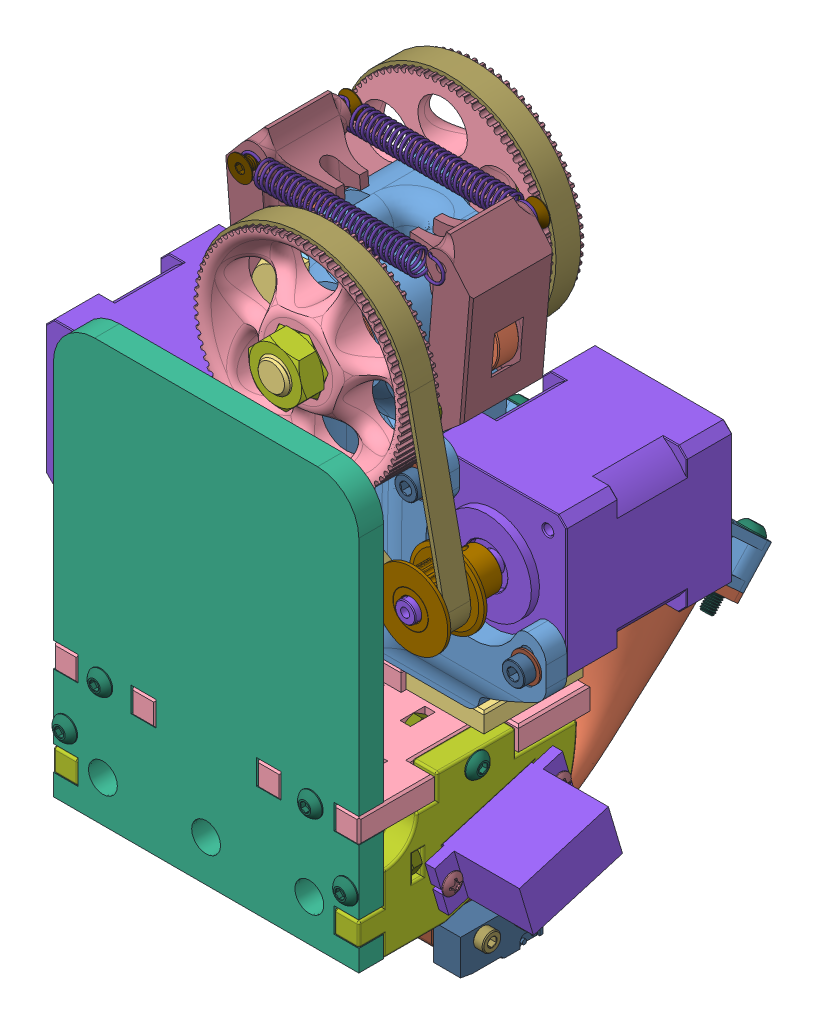
SolidWorks assembly Assembly Instructions, configuration Assemble Idler block. Lengths in mm.
Overall size (108.39 160.35 121.94).
110 component instances, 40 part files, 35 mates.
Components (placement in the parent):
- IttyBittyDoubleExtruderAssembly-1: IttyBittyDoubleExtruderAssembly [Default] at origin size (106.39 98.03 74.25)
  - IttyBittyDoubleExtruderBlock-1: IttyBittyDoubleExtruderBlock [Default] at origin size (106.2 79.3 54.92)
  - Bearing-688-1: Bearing-688 [7804K117] at (-8 64.4888 10.5) size (16 16 5)
  - Bearing-688-2: Bearing-688 [7804K117] at (8 64.4888 16.5) size (16 16 5)
  - Bearing-688-3: Bearing-688 [7804K117] at (8 64.4888 -10.5) size (16 16 5)
  - Bearing-688-4: Bearing-688 [7804K117] at (-8 64.4888 -16.5) size (16 16 5)
  - HobbedBolt-1: HobbedBolt [Default] at (8 64.4888 -14) x (0.945139 -0.326669 0) z (0 0 1) size (14.66 12.7 56.13)
  - Parametric-Pulley-80-8-hex-1: Parametric-Pulley-80-8-hex [Default] at (8 64.4888 32) x (0.986927 0.161169 0) z (0 0 -1) size (50.4 50.4 9.47)
  - Spacer 1mm-1: Spacer 1mm [Default] at (8 64.4888 -14) size (13 13 1)
  - Spacer 2mm-1: Spacer 2mm [Default] at (8 64.4888 19) size (13 13 2)
  - HobbedBolt-2: HobbedBolt [Default] at (-8 64.4888 14) x (-0.397408 -0.917642 0) z (0 0 -1) size (14.66 12.7 56.13)
  - Parametric-Pulley-80-8-hex-2: Parametric-Pulley-80-8-hex [Default] at (-8 64.4888 -32) x (1 0 0) z (0 0 1) size (50.4 50.4 9.47)
  - Spacer 1mm-2: Spacer 1mm [Default] at (-8 64.4888 14) x (-0.923728 -0.383049 0) z (0 0 -1) size (13 13 1)
  - Spacer 2mm-2: Spacer 2mm [Default] at (-8 64.4888 -21) size (13 13 2)
  - 5-16-Nut-1: 5-16-Nut [Default] at (-8 64.4888 -30.3) size (14.66 12.7 5.2)
  - 5-16-Nut-2: 5-16-Nut [Default] at (8 64.4888 25.1) x (0.353886 0.935288 0) z (0 0 1) size (14.66 12.7 5.2)
  - 5-16-Nut-3: 5-16-Nut [Default] at (8 64.4888 30.3) x (0.969294 -0.245906 0) z (0 0 1) size (14.66 12.7 5.2)
  - 5-16-Nut-4: 5-16-Nut [Default] at (-8 64.4888 -35.5) x (0.948708 -0.316153 0) z (0 0 1) size (14.66 12.7 5.2)
  - NEMA14 Stepper Motor-1: NEMA14 Stepper Motor [Default] at (17.9692 8.8788 -30.1574) x (-1 0 0) z (0 1 0) size (36.32 61.75 35.05)
  - GT2_20tooth-1: GT2_20tooth [Default] at (35.4952 26.4048 12.75) x (0 0 1) z (-0.834274 -0.551351 0) size (17.5 18 18)
  - GT2_20tooth-2: GT2_20tooth [Default] at (-35.4952 26.4048 -12.75) x (0 0 -1) z (0.834274 -0.551351 0) size (17.5 18 18)
  - NEMA14 Stepper Motor-2: NEMA14 Stepper Motor [Default] at (-17.9692 8.8788 30.1574) x (1 0 0) z (0 1 0) size (36.32 61.75 35.05)
  - M3x10HexCapScrew-1: M3x10HexCapScrew [91290A115] at (22.5 13.4 5.45) x (-0.709862 0.70434 0) z (0 0 -1) size (5.5 5.5 13.21)
  - M3Washer-1: M3Washer [91166A210] at (22.5 13.4 15) x (0.895294 -0.445476 0) z (0 0 -1) size (7 7 0.45)
  - M3Washer-12: M3Washer [91166A210] at (-22.5 13.4 -15) x (-0.895294 -0.445476 0) z (0 0 1) size (7 7 0.45)
  - M3x10HexCapScrew-5: M3x10HexCapScrew [91290A115] at (-22.5 13.4 -5.45) x (0.709862 0.70434 0) z (0 0 1) size (5.5 5.5 13.21)
  - M3Washer-13: M3Washer [91166A210] at (22.5 39.4 15) x (0.895294 -0.445476 0) z (0 0 -1) size (7 7 0.45)
  - M3Washer-14: M3Washer [91166A210] at (48.5 13.4 15) x (0.895294 -0.445476 0) z (0 0 -1) size (7 7 0.45)
  - M3x10HexCapScrew-6: M3x10HexCapScrew [91290A115] at (22.5 39.4 5.45) x (-0.709862 0.70434 0) z (0 0 -1) size (5.5 5.5 13.21)
  - M3x10HexCapScrew-7: M3x10HexCapScrew [91290A115] at (48.5 13.4 5.45) x (-0.709862 0.70434 0) z (0 0 -1) size (5.5 5.5 13.21)
  - M3Washer-16: M3Washer [91166A210] at (-22.5 39.4 -15) x (-0.895294 -0.445476 0) z (0 0 1) size (7 7 0.45)
  - M3Washer-17: M3Washer [91166A210] at (-48.5 13.4 -15) x (-0.895294 -0.445476 0) z (0 0 1) size (7 7 0.45)
  - M3x10HexCapScrew-9: M3x10HexCapScrew [91290A115] at (-22.5 39.4 -5.45) x (0.709862 0.70434 0) z (0 0 1) size (5.5 5.5 13.21)
  - M3x10HexCapScrew-10: M3x10HexCapScrew [91290A115] at (-48.5 13.4 -5.45) x (0.709862 0.70434 0) z (0 0 1) size (5.5 5.5 13.21)
  - DriveBelt-1: DriveBelt [Default] at (0 0 25.5) x (-1 0 0) z (0 0 -1) size (60.34 70.93 6)
  - DriveBelt-2: DriveBelt [Default] at (0 0 -25.5) size (60.34 70.93 6)
  - IdlerBlock-1: IdlerBlock [Default] at (21.104 63.5553 0) x (-0.996453 0.084148 0) z (0 0 -1) size (20.98 41.13 20.11)
  - Bearing-688-5: Bearing-688 [7804K117] at (21.104 63.5553 0) x (0.754304 -0.656525 0) z (0 0 1) size (16 16 5)
  - IdlerPin-15mm-1: IdlerPin-15mm [Default] at (21.104 63.5553 0) x (-0.996453 0.084148 0) z (0 0 1) size (7.5 8 15.6)
  - M3x25-1: M3x25 [91290A125] at (20.0438 51 15) x (0.098651 -0.995122 0) z (0 0 1) size (5.5 5.5 28.26)
  - M3HexNut-1: M3HexNut [90591A121] at (20.0438 51 11.2) x (0.996239 -0.086644 0) z (-0.086644 -0.996239 0) size (5.5 2.58 6.35)
  - M3HexNut-2: M3HexNut [90591A121] at (-20.0438 51 -11.2) x (-0.996239 -0.086644 0) z (0.086644 -0.996239 0) size (5.5 2.58 6.35)
  - M3x25-2: M3x25 [91290A125] at (-20.0438 51 -15) x (-0.098651 -0.995122 0) z (0 0 -1) size (5.5 5.5 28.26)
  - IdlerPin-15mm-2: IdlerPin-15mm [Default] at (-21.104 63.5553 0) x (0.996453 0.084148 0) z (0 0 -1) size (7.5 8 15.6)
  - Bearing-688-6: Bearing-688 [7804K117] at (-21.104 63.5553 0) x (-0.754304 -0.656525 0) z (0 0 -1) size (16 16 5)
  - IdlerBlock-2: IdlerBlock [Default] at (-21.104 63.5553 0) x (0.996453 0.084148 0) z (0 0 1) size (20.98 41.13 20.11)
  - ExtensionSpring-1: ExtensionSpring [extended] at (-62.7334 81.5024 -11.4843) size (49.53 5.74 5.79)
  - ExtensionSpring-2: ExtensionSpring [extended] at (62.7334 81.5024 11.4843) x (-1 0 0) z (0 0 -1) size (49.53 5.74 5.79)
  - M3x12HexFlatScrew-1: M3x12HexFlatScrew [92125A132] at (22.6187 81.4915 -13.5) x (0.115685 0.993286 0) z (0 0 -1) size (6 6 12.31)
  - M3x12HexFlatScrew-2: M3x12HexFlatScrew [92125A132] at (22.6188 81.4921 13.5) x (-0.115685 -0.993286 0) z (0 0 1) size (6 6 12.31) (hidden)
  - M3x12HexFlatScrew-3: M3x12HexFlatScrew [92125A132] at (-22.6188 81.4921 -13.5) x (0.115685 -0.993286 0) z (0 0 -1) size (6 6 12.31)
  - M3x12HexFlatScrew-4: M3x12HexFlatScrew [92125A132] at (-22.6187 81.4915 13.5) x (-0.115685 0.993286 0) z (0 0 1) size (6 6 12.31)
  - M3HexNut-3: M3HexNut [90591A121] at (0 1.2 7.5) x (0.866025 0 -0.5) z (0.5 0 0.866025) size (5.5 2.58 6.35)
  - M3HexNut-4: M3HexNut [90591A121] at (0 1.2 -7.5) x (0.866025 0 0.5) z (-0.5 0 0.866025) size (5.5 2.58 6.35)
  - M4HexNut-1: M4HexNut [91828A231] at (-24.875 1.6 0) x (0 0 -1) z (1 0 0) size (7 3.44 8.08)
  - M4HexNut-2: M4HexNut [91828A231] at (24.875 1.6 0) x (0 0 -1) z (1 0 0) size (7 3.44 8.08)
- PartCoolingDoubleFanShroud-1: PartCoolingDoubleFanShroud [Default] at (0 -14.2905 -53.1989) x (1 0 0) z (0 -0.679891 -0.733313)
- DoubleGrooveMount-1: DoubleGrooveMount [Default] at (0 -4.6 0) x (1 0 0) z (0 0 -1)
- XCarriageShelfAssembly-1: XCarriageShelfAssembly [Default] at (0 -9.6 38.3) size (93.97 118.63 57.77) (flexible)
  - XCarriageDoubleShelf-1: XCarriageDoubleShelf [Default] at (-37 0 -50) x (1 0 0) z (0 0 -1) size (74 10.95 56)
  - 25x25x10Fan-1: 25x25x10Fan [Default] at (-0.033 8 -12.717) x (1 0 0) z (0 -1 0) size (25 25 10)
  - XCarriageBackPlate-1: XCarriageBackPlate [Default] at (-37 -32.5 0) size (74 101.26 6)
  - ServoShelfBracket-1: ServoShelfBracket [Hot End Wiring Vent] at (-31 -6 0) x (0 0 -1) z (1 0 0) size (53 32.5 6)
  - ServoShelfBracket-2: ServoShelfBracket [HXT900] at (37 -6 0) x (0 0 -1) z (1 0 0) size (53 32.5 6)
  - Servo-HXT900-1: Servo-HXT900 [Default] at (55.2 -23.6377 -24.0991) x (0 -0.284598 0.958647) z (-1 0 0) size (32.3 12 29.6)
  - ZProbeAssembly-2: ZProbeAssembly [Default] at (38.1869 -15.2241 -18.2942) x (0 -0.999999 0.001104) z (0 -0.001104 -0.999999) size (39.46 14.76 19.99)
    - Servo Horn-1: Servo Horn [Default] at (34.2536 11.8969 23.9402) size (19.66 4.12 7.35)
    - SnapLimitSwitch-1: SnapLimitSwitch [Default] at (22.9628 5.2957 11.2222) x (0.000181 0 -1) z (0 -1 0) size (19.99 14.86 6.5)
    - ZProbeArmMirrored-1: ZProbeArmMirrored [Default] at (-0.0025 17.1137 27.8606) x (1 0 0.000181) z (0.000181 0 -1) size (33.66 4.95 19.95)
    - M2.5x10HexSocketScrew-1: M2.5x10HexSocketScrew [91292A014] at (25.3259 12.0445 6.4347) x (-0.001575 0 0.999999) z (0 1 0) size (4.5 4.5 13.01)
    - M2.5x10HexSocketScrew-2: M2.5x10HexSocketScrew [91292A014] at (25.3241 12.0445 15.9347) x (-0.043466 0 0.999055) z (0 1 0) size (4.5 4.5 13.01)
    - ServoScrew-1: ServoScrew [93406A071] at (1.841 12.5869 13.9305) x (0.770997 0 -0.636839) z (0 1 0) size (4.93 5.18 10.49)
  - TightDoubleHexagonShroud-1: TightDoubleHexagonShroud [No Support] at (0 -6 0) x (1 0 0) z (0 0 -1) size (57.71 23.73 44.86)
  - M3HexNut-1: M3HexNut [90591A121] at (25.5 -3 -8.2) x (0.5 -0.866025 0) z (-0.866025 -0.5 0) size (5.5 2.58 6.35)
  - M3HexNut-2: M3HexNut [90591A121] at (-25.5 -3 -8.2) x (0.5 0.866025 0) z (0.866025 -0.5 0) size (5.5 2.58 6.35)
  - M3HexNut-3: M3HexNut [90591A121] at (22.8 -3 -22.5) x (0 0.866025 -0.5) z (0 -0.5 -0.866025) size (5.5 2.58 6.35)
  - M3HexNut-4: M3HexNut [90591A121] at (34 -17 -8.2) x (0 -1 0) z (-1 0 0) size (5.5 2.58 6.35)
  - M3HexNut-5: M3HexNut [90591A121] at (-22.8 -3 -22.5) x (0 0 1) z (0 -1 0) size (5.5 2.58 6.35)
  - M3HexNut-6: M3HexNut [90591A121] at (-34 -17 -8.2) x (0.866025 -0.5 0) z (-0.5 -0.866025 0) size (5.5 2.58 6.35)
  - M3x16HexButtonScrew-1: M3x16HexButtonScrew [92095A184] at (-34 -16.66 7.65) x (-0.942036 0.335513 0) z (0 0 1) size (5.7 5.7 18)
  - M3x16HexButtonScrew-2: M3x16HexButtonScrew [92095A184] at (34 -16.66 7.65) x (-0.968696 0.248251 0) z (0 0 1) size (5.7 5.7 18)
  - M3x16HexButtonScrew-3: M3x16HexButtonScrew [92095A184] at (-38.65 -3 -22.5) x (0 0 -1) z (-1 0 0) size (5.7 5.7 18)
  - M3x16HexButtonScrew-4: M3x16HexButtonScrew [92095A184] at (-25.5 -2.66 7.65) x (-0.942623 0.333859 0) z (0 0 1) size (5.7 5.7 18)
  - M3x16HexButtonScrew-5: M3x16HexButtonScrew [92095A184] at (25.5 -2.66 7.65) x (-0.602879 0.797832 0) z (0 0 1) size (5.7 5.7 18)
  - M3x16HexButtonScrew-6: M3x16HexButtonScrew [92095A184] at (38.65 -3 -22.5) x (0 0 1) z (1 0 0) size (5.7 5.7 18)
  - ServoScrew-1: ServoScrew [93406A071] at (39.4 -22.4735 -14.0563) x (0 0 1) z (1 0 0) size (4.93 5.18 10.49)
  - ServoScrew-2: ServoScrew [93406A071] at (39.4 -14.6755 -40.3232) x (0 0 1) z (1 0 0) size (4.93 5.18 10.49)
  - M3x6HexButtonScrew-1: M3x6HexButtonScrew [92095A179] at (-20 -8.85 -15) x (0.993499 0 -0.113843) z (0 -1 0) size (5.7 5.7 7.94)
  - M3x6HexButtonScrew-2: M3x6HexButtonScrew [92095A179] at (20 -8.85 -15) x (1 0 0) z (0 -1 0) size (5.7 5.7 7.94)
  - M3x12HexFlatScrew-1: M3x12HexFlatScrew [92125A132] at (-10.033 -6 -2.717) x (1 0 0) z (0 -1 0) size (6 6 12.31)
  - M3x12HexFlatScrew-2: M3x12HexFlatScrew [92125A132] at (9.967 -6 -22.717) x (1 0 0) z (0 -1 0) size (6 6 12.31)
  - M3x12HexFlatScrew-3: M3x12HexFlatScrew [92125A132] at (9.967 -6 -2.717) x (1 0 0) z (0 -1 0) size (6 6 12.31)
- HexagonAssembled-1: HexagonAssembled [Default] at (-3.9618 -44.0544 0.5889) x (-0.982838 0 0.184472) z (-0.184472 0 -0.982838) size (20 54.51 24.04)
  - HexagonHotEnd-1: HexagonHotEnd [Default] at (-13.8308 34.4544 -1.9967) size (16 54.51 22.04)
  - HexagonBlockInsulator-1: HexagonBlockInsulator [Default] at origin size (20 12.11 22)
- HexagonAssembled-2: HexagonAssembled [Default] at (-11.0086 -44.0544 -13.9377) x (-0.213949 0 -0.976845) z (0.976845 0 -0.213949) size (20 54.51 24.04)
  - HexagonHotEnd-1: HexagonHotEnd [Default] at (-13.8308 34.4544 -1.9967) size (16 54.51 22.04)
  - HexagonBlockInsulator-1: HexagonBlockInsulator [Default] at origin size (20 12.11 22)
- 40x40x10Fan-1: 40x40x10Fan [Default] at (0 -6.9574 -59.9978) x (0 0.679891 0.733313) z (0 -0.733313 0.679891)
- M3x16HexButtonScrew-1: M3x16HexButtonScrew [92095A184] at (-16 -16.6257 -72.8526) x (-0.777621 -0.42747 -0.461058) z (0 0.733313 -0.679891) size (5.7 5.7 18)
- M3x16HexButtonScrew-2: M3x16HexButtonScrew [92095A184] at (-16 5.1309 -49.3866) x (-0.777621 -0.42747 -0.461058) z (0 0.733313 -0.679891) size (5.7 5.7 18)
- M3x16HexButtonScrew-3: M3x16HexButtonScrew [92095A184] at (16 -16.6257 -72.8526) x (-0.777621 -0.42747 -0.461058) z (0 0.733313 -0.679891) size (5.7 5.7 18)
- M3x16HexButtonScrew-4: M3x16HexButtonScrew [92095A184] at (16 5.1309 -49.3866) x (-0.777621 -0.42747 -0.461058) z (0 0.733313 -0.679891) size (5.7 5.7 18)
- M3x25HexSocketScrew-1: M3x25HexSocketScrew [91292A020] at (17.5 0.4 -30) x (0 0 -1) z (1 0 0)
- M3HexNut-2: M3HexNut [90591A121] at (8.7 0.4 -30) x (0 -1 0) z (0 0 1) size (5.5 2.58 6.35)
- M4x20HexButtonScrew-1: M4x20HexButtonScrew [92095A196] at (-24.875 -17.8 0) x (1 0 0) z (0 -1 0)
- M4x20HexButtonScrew-2: M4x20HexButtonScrew [92095A196] at (24.875 -17.8 0) x (1 0 0) z (0 -1 0)
- M3x12HexFlatScrew-1: M3x12HexFlatScrew [92125A132] at (0 -9.6 -7.5) x (0.605151 0 -0.796111) z (0 -1 0) size (6 6 12.31)
- M3x12HexFlatScrew-2: M3x12HexFlatScrew [92125A132] at (0 -9.6 7.5) x (0.605151 0 -0.796111) z (0 -1 0) size (6 6 12.31)
- Insulator-1: Insulator [Default] at (22.5 -38.525 1.5) x (-1 0 0) z (0 0 1) size (48 1.25 26)
Mates (geometry in assembly coordinates):
- Coincident1: coincident aligned: plane of IttyBittyDoubleExtruderAssembly-1/IttyBittyDoubleExtruderBlock-1 through (0 0 0) normal (0 1 0); plane of assembly through (0 0 0) normal (0 1 0)
- Coincident2: coincident aligned: plane of IttyBittyDoubleExtruderAssembly-1/IttyBittyDoubleExtruderBlock-1 through (0 0 0) normal (1 0 0); plane of assembly through (0 0 0) normal (1 0 0)
- Coincident3: coincident aligned: plane of IttyBittyDoubleExtruderAssembly-1/IttyBittyDoubleExtruderBlock-1 through (0 0 0) normal (0 0 1); plane of assembly through (0 0 0) normal (0 0 1)
- Concentric1: concentric aligned: cylinder of IttyBittyDoubleExtruderAssembly-1/IttyBittyDoubleExtruderBlock-1 through (4.4 0.4 -30) axis (-1 0 0) radius 1.7; cylinder of PartCoolingDoubleFanShroud-1 through (21.1857 0.4 -30) axis (-1 0 0) radius 1.7
- Coincident4: coincident aligned: plane of PartCoolingDoubleFanShroud-1; plane of assembly through (0 0 0) normal (1 0 0)
- Concentric22: concentric anti-aligned: cylinder of IttyBittyDoubleExtruderAssembly-1/IttyBittyDoubleExtruderBlock-1 through (-10 -4.6 0) axis (0 1 0) radius 8.5; cylinder of HexagonAssembled-2/HexagonHotEnd-1 through (-10 -0.2 0) axis (0 -1 0) radius 8
- Concentric29: concentric aligned: circle of PartCoolingDoubleFanShroud-1; cylinder of 40x40x10Fan-1 through (16 -3.4122 -41.4659) axis (0 0.733313 -0.679891) radius 1.778
- Concentric30: concentric aligned: circle of PartCoolingDoubleFanShroud-1; cylinder of 40x40x10Fan-1 through (-16 -25.1688 -64.9319) axis (0 0.733313 -0.679891) radius 1.778
- Coincident63: coincident anti-aligned: plane of PartCoolingDoubleFanShroud-1 through (0 -14.2905 -53.1989) normal (0 0.733313 -0.679891); plane of 40x40x10Fan-1 through (0 -14.2905 -53.1989) normal (0 -0.733313 0.679891)
- Concentric31: concentric anti-aligned: circle of 40x40x10Fan-1; circle of M3x16HexButtonScrew-1
- Coincident64: coincident anti-aligned: plane of 40x40x10Fan-1 through (16 3.9209 -48.2648) normal (0 0.733313 -0.679891); plane of M3x16HexButtonScrew-1 through (-14.2081 -19.3424 -73.356) normal (0 -0.733313 0.679891)
- Concentric32: concentric anti-aligned: cylinder of PartCoolingDoubleFanShroud-1 through (21.1857 0.4 -30) axis (-1 0 0) radius 1.7; cylinder of M3x25HexSocketScrew-1 through (-10.5 0.4 -30) axis (1 0 0) radius 2.75
- Coincident65: coincident anti-aligned: plane of PartCoolingDoubleFanShroud-1 through (-7.5 -339959.9428 -366709.6505) normal (-1 0 0); plane of M3x25HexSocketScrew-1 through (-7.5 0.4 -30) normal (1 0 0)
- Coincident66: coincident anti-aligned: cylinder of M3x25HexSocketScrew-1 through (-10.5 0.4 -30) axis (1 0 0) radius 2.75; circle of M3HexNut-2
- Coincident67: coincident anti-aligned: plane of PartCoolingDoubleFanShroud-1 through (7.5 -339959.9428 -366709.6505) normal (1 0 0); plane of M3HexNut-2 through (7.5 -2.35 -31.5877) normal (-1 0 0)
- Concentric33: concentric anti-aligned: cylinder of XCarriageShelfAssembly-1/XCarriageDoubleShelf-1 through (-24.875 -15.6 0) axis (0 1 0) radius 2.2; circle of M4x20HexButtonScrew-1
- Coincident68: coincident anti-aligned: plane of XCarriageShelfAssembly-1/XCarriageDoubleShelf-1 through (-37 -15.6 -11.7) normal (0 -1 0); plane of M4x20HexButtonScrew-1 through (-24.875 -15.6 -3.8) normal (0 1 0)
- Concentric34: concentric anti-aligned: cylinder of XCarriageShelfAssembly-1/XCarriageDoubleShelf-1 through (24.875 -15.6 0) axis (0 1 0) radius 2.2; circle of M4x20HexButtonScrew-2
- Coincident69: coincident anti-aligned: plane of XCarriageShelfAssembly-1/XCarriageDoubleShelf-1 through (-37 -15.6 -11.7) normal (0 -1 0); plane of M4x20HexButtonScrew-2 through (24.875 -15.6 -3.8) normal (0 1 0)
- Concentric35: concentric anti-aligned: cylinder of IttyBittyDoubleExtruderAssembly-1/IttyBittyDoubleExtruderBlock-1 through (0 -4.6 -7.5) axis (0 1 0) radius 1.7; circle of M3x12HexFlatScrew-1
- Coincident71: coincident anti-aligned: plane of IttyBittyDoubleExtruderAssembly-1/IttyBittyDoubleExtruderBlock-1 through (0 -4.6 0) normal (0 -1 0); plane of DoubleGrooveMount-1 through (0 -4.6 0) normal (0 1 0)
- Parallel1: parallel aligned: plane of IttyBittyDoubleExtruderAssembly-1/IttyBittyDoubleExtruderBlock-1 through (15.1741 31.9778 -13) normal (0 0 -1); plane of DoubleGrooveMount-1 through (0 -9.6 -12) normal (0 0 -1)
- Concentric36: concentric anti-aligned: cylinder of DoubleGrooveMount-1 through (-10 -9.6 0) axis (0 1 0) radius 6.075; cylinder of HexagonAssembled-2/HexagonHotEnd-1 through (-10 -4.96 0) axis (0 -1 0) radius 6
- Coincident73: coincident anti-aligned: plane of DoubleGrooveMount-1 through (0 -9.6 0) normal (0 -1 0); plane of HexagonAssembled-1/HexagonHotEnd-1 through (10 -9.6 0) normal (0 1 0)
- Coincident74: coincident anti-aligned: plane of DoubleGrooveMount-1 through (0 -9.6 0) normal (0 -1 0); plane of HexagonAssembled-2/HexagonHotEnd-1 through (-10 -9.6 0) normal (0 1 0)
- Coincident75: coincident anti-aligned: plane of DoubleGrooveMount-1 through (0 -9.6 0) normal (0 -1 0); plane of XCarriageShelfAssembly-1/XCarriageDoubleShelf-1 through (-37 -9.6 -11.7) normal (0 1 0)
- Concentric37: concentric anti-aligned: cylinder of DoubleGrooveMount-1 through (-24.875 -9.6 0) axis (0 1 0) radius 2.5; circle of XCarriageShelfAssembly-1/XCarriageDoubleShelf-1
- Concentric38: concentric aligned: cylinder of DoubleGrooveMount-1 through (24.875 -9.6 0) axis (0 1 0) radius 2.5; circle of XCarriageShelfAssembly-1/XCarriageDoubleShelf-1
- Coincident76: coincident aligned: plane of DoubleGrooveMount-1 through (0 -9.6 0) normal (0 -1 0); plane of M3x12HexFlatScrew-1 through (-1.1942 -9.6 -8.4077) normal (0 -1 0)
- Coincident77: coincident aligned: plane of DoubleGrooveMount-1 through (0 -9.6 0) normal (0 -1 0); plane of M3x12HexFlatScrew-2 through (-1.1942 -9.6 6.5923) normal (0 -1 0)
- Concentric39: concentric anti-aligned: cylinder of IttyBittyDoubleExtruderAssembly-1/IttyBittyDoubleExtruderBlock-1 through (0 -4.6 7.5) axis (0 1 0) radius 1.7; circle of M3x12HexFlatScrew-2
- Distance1: distance = 0.5 mm anti-aligned: plane of Insulator-1 through (-25.5 -37.9 -10.88) normal (0 1 0); plane of XCarriageShelfAssembly-1/TightDoubleHexagonShroud-1 through (0.45 -37.4 -5.75) normal (0 -1 0)
- Concentric41: concentric anti-aligned: cylinder of IttyBittyDoubleExtruderAssembly-1/IttyBittyDoubleExtruderBlock-1 through (10 -4.6 0) axis (0 1 0) radius 8.5; cylinder of HexagonAssembled-1/HexagonHotEnd-1 through (10 -0.2 0) axis (0 -1 0) radius 8
- Concentric42: concentric anti-aligned: cylinder of HexagonAssembled-1/HexagonHotEnd-1 through (10 -39.6 0) axis (0 1 0) radius 2; cylinder of Insulator-1 through (10 -37.9 0) axis (0 -1 0) radius 2.5
- Concentric43: concentric anti-aligned: cylinder of HexagonAssembled-2/HexagonHotEnd-1 through (-10 -39.6 0) axis (0 1 0) radius 2; cylinder of Insulator-1 through (-10 -37.9 0) axis (0 -1 0) radius 2.5
